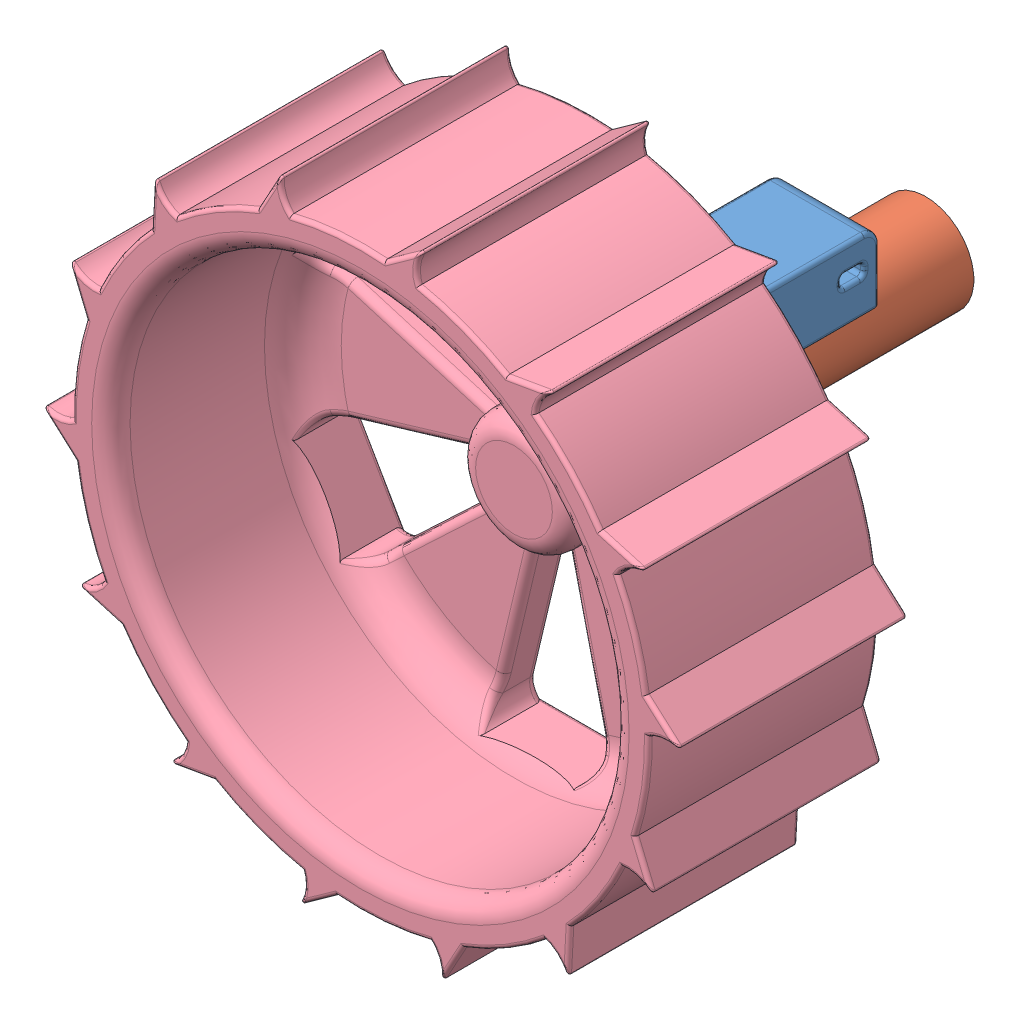
SolidWorks assembly Wheel Motor Subassembly, configuration Right. Lengths in mm.
Overall size (165.6 162.92 147.6).
4 component instances, 4 part files, 12 mates.
Components (placement in the parent):
- Drive Motor Mount-1: Drive Motor Mount [Default] at origin size (25.4 37.4 52.5)
- BEMONOC 25GA370-1: BEMONOC 25GA370 [Default] at (0 0 -74.8) size (25 25 86.3)
- Flange Coupling-1: Flange Coupling [Default] at (0 0 12.5) x (1 0 0) z (0 -1 0) size (22 12 22)
- PaddleWheel-2: PaddleWheel [Right] at (0 0 12.5) x (-1 0 0) z (0 0 -1) size (165.6 162.92 60.59)
Mates (geometry in assembly coordinates):
- Coincident1: coordinate: point of Drive Motor Mount-1
- Coincident2: coincident anti-aligned: plane of Drive Motor Mount-1 through (0 0 0) normal (0 0 -1); plane of BEMONOC 25GA370-1 through (0 0 0) normal (0 0 1)
- Concentric1: concentric anti-aligned: cylinder of Drive Motor Mount-1 through (8.5 0 2.5) axis (0 0 -1) radius 1.6; cylinder of BEMONOC 25GA370-1 through (8.5 0 -4) axis (0 0 1) radius 1.5
- Concentric2: concentric anti-aligned: cylinder of Drive Motor Mount-1 through (-8.5 0 2.5) axis (0 0 -1) radius 1.6; cylinder of BEMONOC 25GA370-1 through (-8.5 0 -4) axis (0 0 1) radius 1.5
- Concentric3: concentric anti-aligned: cylinder of BEMONOC 25GA370-1 through (0 0 11.5) axis (0 0 -1) radius 2; cylinder of Flange Coupling-1 through (0 0 10.5) axis (0 0 1) radius 2
- Coincident3: coincident anti-aligned: plane of BEMONOC 25GA370-1 through (0 0 0.5) normal (0 0 1); plane of Flange Coupling-1 through (0 0 0.5) normal (0 0 -1)
- Coincident4: coincident anti-aligned: plane of Flange Coupling-1 through (0 0 12.5) normal (0 0 1); plane of PaddleWheel-2 through (0 0 12.5) normal (0 0 -1)
- Concentric4: concentric anti-aligned: cylinder of Flange Coupling-1 through (5.5 5.5 10.5) axis (0 0 1) radius 1.425; cylinder of PaddleWheel-2 through (5.5 5.5 22.5) axis (0 0 -1) radius 2
- Concentric5: concentric anti-aligned: cylinder of Flange Coupling-1 through (-5.5 -5.5 10.5) axis (0 0 1) radius 1.425; cylinder of PaddleWheel-2 through (-5.5 -5.5 22.5) axis (0 0 -1) radius 2
- Coincident5: coincident: plane of Flange Coupling-1 through (0 0 12.5) normal (0 0 1); plane of PaddleWheel-1 through (0 0 12.5) normal (0 0 -1)
- Concentric6: concentric: cylinder of Flange Coupling-1 through (-5.5 5.5 10.5) axis (0 0 1) radius 1.425; cylinder of PaddleWheel-1 through (-5.5 5.5 22.5) axis (0 0 -1) radius 1.375
- Concentric7: concentric anti-aligned: cylinder of Flange Coupling-1 through (5.5 -5.5 10.5) axis (0 0 1) radius 1.425; cylinder of PaddleWheel-1 through (5.5 -5.5 22.5) axis (0 0 -1) radius 1.375
